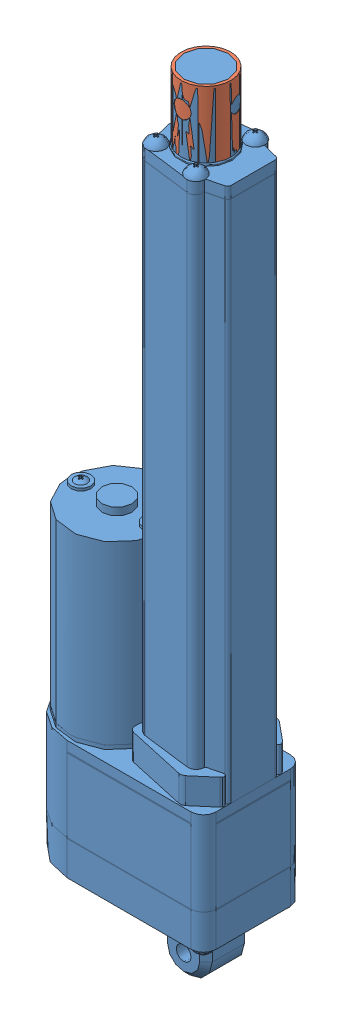
SolidWorks assembly UOR22-ARM-2-A-003, configuration Default. Lengths in mm.
Overall size (75.05 314 40).
2 component instances, 2 part files, 2 mates.
Components (placement in the parent):
- FA-OS-35(200)-12-6-1: FA-OS-35(200)-12-6 [Default] at (103.3637 94.9071 228.4325) x (1 0 0) z (0 1 0) size (75.05 40 314)
- actuator extension-1: actuator extension [Default] at (139.3637 107.9632 228.4325) x (0.303562 0 0.952812) z (-0.952812 0 0.303562) size (19.99 228.6 19.99)
Mates (geometry in assembly coordinates):
- Concentric1: concentric aligned: circle of FA-OS-35(200)-12-6-1; circle of actuator extension-1
- LimitDistance1: limit distance = 0 mm aligned: plane of FA-OS-35(200)-12-6-1 through (139.3637 336.5632 228.4325) normal (0 1 0); plane of actuator extension-1 through (139.3637 336.5632 228.4325) normal (0 1 0)
